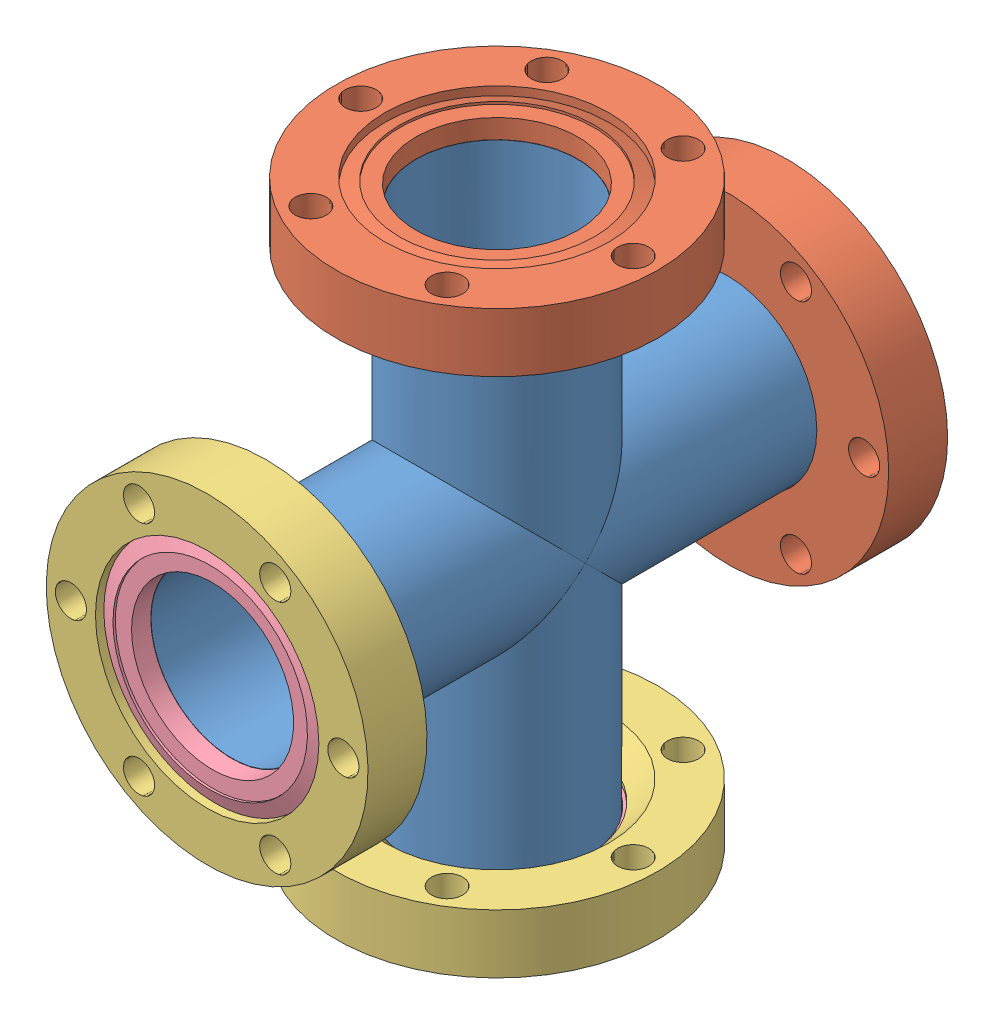
SolidWorks assembly 2.75 Four Way Cross, configuration Default. Lengths in mm.
Overall size (69.34 124.92 124.92).
10 component instances, 4 part files, 0 mates.
Components (placement in the parent):
- 405002 P1_405002-001-1: 405002 P1_405002-001 [Default] at origin size (38.83 38.83 115)
- 405002 P1_405002-001-2: 405002 P1_405002-001 [Default] at (0 -57.15 57.15) x (1 0 0) z (0 1 0) size (38.83 38.83 115)
- 405002 P2_110014 (2.75 X 1.5 NR)_1-1: 405002 P2_110014 (2.75 X 1.5 NR)_1 [Default] at (0 56.1086 57.15) x (0 1 0) z (1 0 0) size (12.7 69.34 69.34)
- 405002 P2_110014 (2.75 X 1.5 NR)_1-2: 405002 P2_110014 (2.75 X 1.5 NR)_1 [Default] at (0 0 1.0414) x (0 0 -1) z (1 0 0) size (12.7 69.34 69.34)
- 405002 P3_100014 (2.75 X 1.5 R)_1-1: 405002 P3_100014 (2.75 X 1.5 R)_1 [Default] at (0 0 119.6086) x (0 0 -1) z (1 0 0) size (12.7 69.34 69.34)
  - 405002 P4_100014 (2.75 X 1.5 REC)_1-1: 405002 P4_100014 (2.75 X 1.5 REC)_1 [Default] at origin size (12.7 69.34 69.34)
  - 405002 P5_100014 (2.75 X 1.5 INS)_1-1: 405002 P5_100014 (2.75 X 1.5 INS)_1 [Default] at (1.17 0 0) x (1 0 0) z (0 0.994423 -0.105464) size (6.96 48.1 48.1)
- 405002 P3_100014 (2.75 X 1.5 R)_1-2: 405002 P3_100014 (2.75 X 1.5 R)_1 [Default] at (0 -62.4586 57.15) x (0 1 0) z (-1 0 0) size (12.7 69.34 69.34)
  - 405002 P4_100014 (2.75 X 1.5 REC)_1-1: 405002 P4_100014 (2.75 X 1.5 REC)_1 [Default] at origin size (12.7 69.34 69.34)
  - 405002 P5_100014 (2.75 X 1.5 INS)_1-1: 405002 P5_100014 (2.75 X 1.5 INS)_1 [Default] at (1.17 0 0) x (1 0 0) z (0 0.994423 -0.105464) size (6.96 48.1 48.1)
